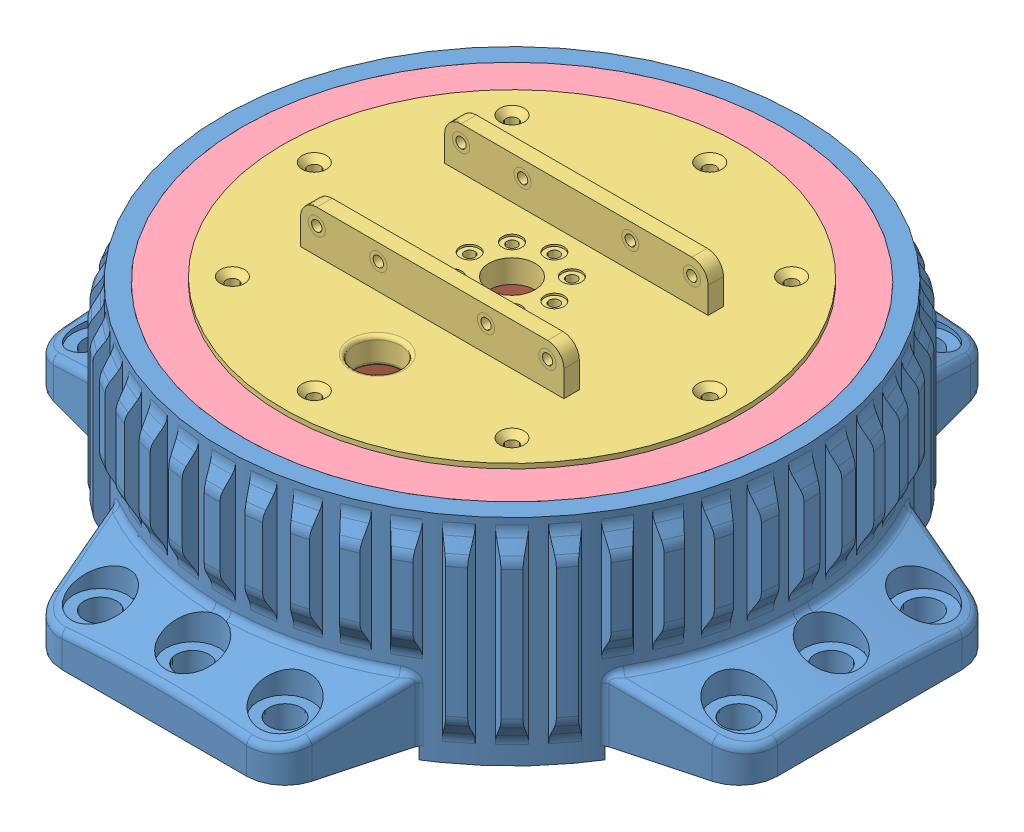
SolidWorks assembly Base_Sim, configuration Default. Lengths in mm.
Overall size (186.5 324.95 596.8).
6 component instances, 5 part files, 10 mates.
Components (placement in the parent):
- J1_Enclosure-1: J1_Enclosure [Default] at origin size (186.5 55.93 186.5)
- J1_Inner_Joint-1: J1_Inner_Joint [Default] at origin size (119 35.75 119)
- J1_Top_Plate-1: J1_Top_Plate [Default] at origin size (119 28.25 119)
- J1_Bearing-2: J1_Bearing [Default] at origin size (140 16 140)
- J1_Bearing-1: J1_Bearing [Default] at (0 32.75 0) size (140 16 140)
- Student_Arm_Geo-1: Student_Arm_Geo [Default] at origin size (0 320.38 548.3)
Mates (geometry in assembly coordinates):
- Coincident1: coincident anti-aligned: plane of J1_Enclosure-1 through (70 -62 0) normal (0 1 0); plane of J1_Bearing-1 through (0 -62 0) normal (0 -1 0)
- Concentric2: concentric anti-aligned: cylinder of J1_Enclosure-1 through (0 -112.0875 0) axis (0 -1 0) radius 70; cylinder of J1_Bearing-1 through (0 -29.25 0) axis (0 1 0) radius 70
- Coincident2: coincident anti-aligned: plane of J1_Enclosure-1 through (66 -78.75 0) normal (0 -1 0); plane of J1_Bearing-2 through (0 -78.75 0) normal (0 1 0)
- Concentric3: concentric anti-aligned: cylinder of J1_Enclosure-1 through (0 -112.0875 0) axis (0 -1 0) radius 70; cylinder of J1_Bearing-2 through (0 -62 0) axis (0 1 0) radius 70
- Concentric4: concentric aligned: cylinder of J1_Top_Plate-1 through (0 -44.75 0) axis (0 1 0) radius 55; cylinder of J1_Bearing-1 through (0 -29.25 0) axis (0 1 0) radius 55
- Coincident3: coincident anti-aligned: plane of J1_Top_Plate-1 through (-55 -46 0) normal (0 -1 0); plane of J1_Bearing-1 through (0 -46 0) normal (0 1 0)
- Coincident4: coincident anti-aligned: plane of J1_Inner_Joint-1 through (-59.5 -94.75 0) normal (0 1 0); plane of J1_Bearing-2 through (0 -94.75 0) normal (0 -1 0)
- Concentric5: concentric anti-aligned: cylinder of J1_Inner_Joint-1 through (0 -112.0875 0) axis (0 -1 0) radius 55; cylinder of J1_Bearing-2 through (0 -62 0) axis (0 1 0) radius 55
- Concentric6: concentric aligned: cylinder of J1_Inner_Joint-1 through (-51.391 -70 0) axis (0 1 0) radius 2.15; cylinder of J1_Top_Plate-1 through (-51.391 -44.75 0) axis (0 1 0) radius 1.6
- Parallel1: parallel aligned: plane of assembly through (0 0 0) normal (0 0 1); plane of J1_Top_Plate-1 through (-30 -38 20.75) normal (0 0 1)
